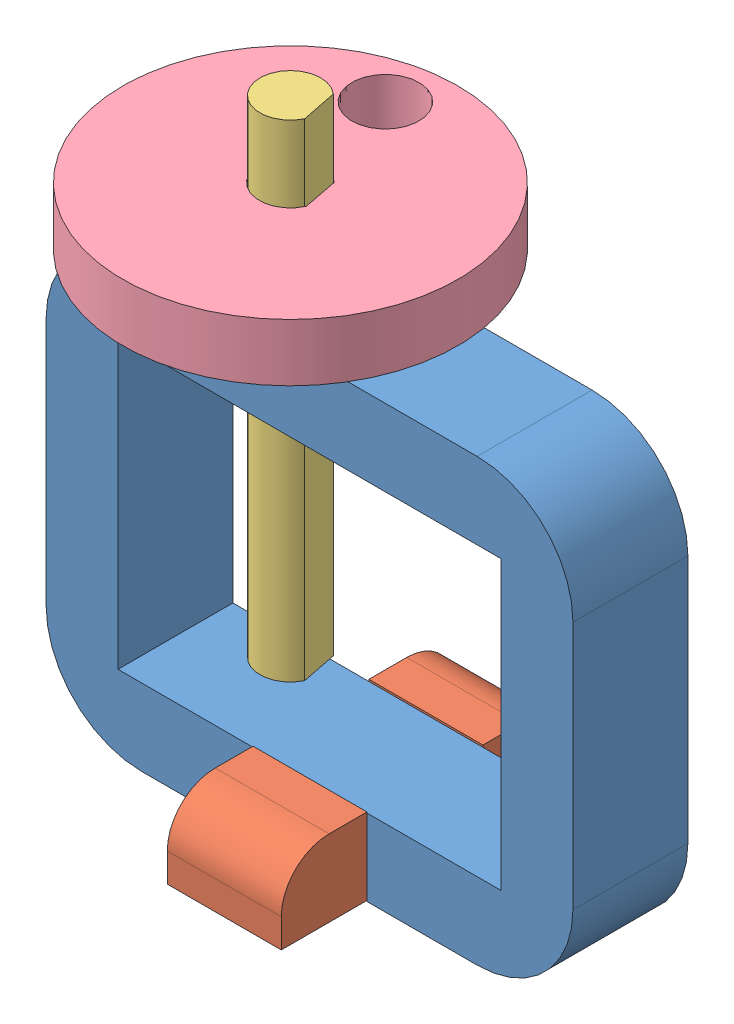
SolidWorks assembly Assem1, configuration Default. Lengths in mm.
Overall size (55.98 62.89 40.97).
4 component instances, 4 part files, 6 mates.
Components (placement in the parent):
- Frame-1: Frame [Default] at (-45.896 -5.1104 27.6906) size (55 46 12)
- Base-1: Base [Default] at (-45.846 -28.0104 27.6406) x (0 0 -1) z (1 0 0) size (30 8 11.9)
- D-shaft-2in-1: D-shaft-2in [Default] at (-53.896 -16.0188 27.6906) x (0.980529 0 -0.196374) z (0.196374 0 0.980529) size (5.71 50.8 6.35)
- knob-1: knob [Default] at (-53.896 26.8896 27.6906) x (0.982085 0 -0.188439) z (-0.188439 0 -0.982085) size (35 9 35)
Mates (geometry in assembly coordinates):
- Coincident1: coincident: plane of Frame-1 through (-45.896 -5.1104 33.6906) normal (0 0 1); plane of Base-1 through (-51.796 -24.1104 33.6906) normal (0 0 -1)
- Coincident2: coincident: plane of Frame-1 through (-39.896 -24.1104 33.6906) normal (-1 0 0); plane of Base-1 through (-39.896 -20.0104 42.6406) normal (1 0 0)
- Coincident3: coincident: plane of Frame-1 through (-45.896 -24.1104 27.6906) normal (0 -1 0); plane of Base-1 through (-45.846 -24.1104 27.6406) normal (0 1 0)
- Concentric1: concentric: cylinder of Frame-1 through (-53.896 17.8896 27.6906) axis (0 -1 0) radius 3.556; cylinder of D-shaft-2in-1 through (-53.896 34.7812 27.6906) axis (0 -1 0) radius 3.175
- Coincident4: coincident: plane of Frame-1 through (-18.396 17.8896 33.6906) normal (0 1 0); plane of knob-1 through (-53.896 17.8896 27.6906) normal (0 -1 0)
- Concentric2: concentric: circle of D-shaft-2in-1; circle of knob-1
